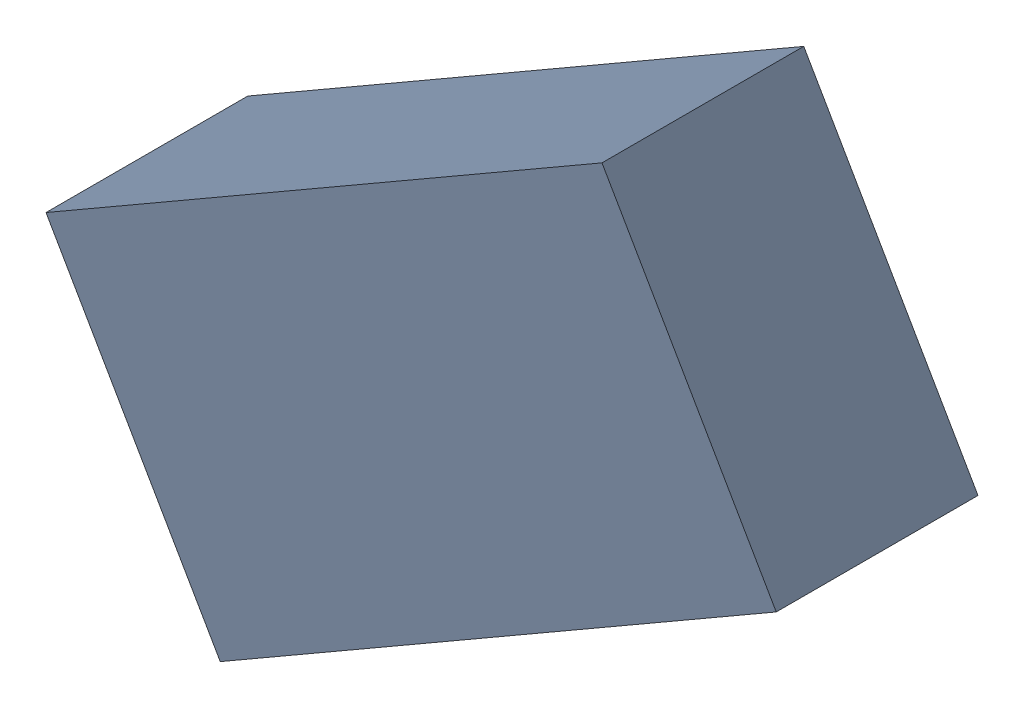
SolidWorks assembly L3_TDA5, configuration Standard. Lengths in mm.
Overall size (1.99 1.7 0.55).
2 component instances, 1 part files, 0 mates.
Components (placement in the parent):
- 885543736-1: 885543736 [Standard] at (-50.8699 -28.6466 0) size (1.99 1.7 0.55)
  - Extruded_21-1: Extruded_21 [Standard] at origin size (1.99 1.7 0.55)
